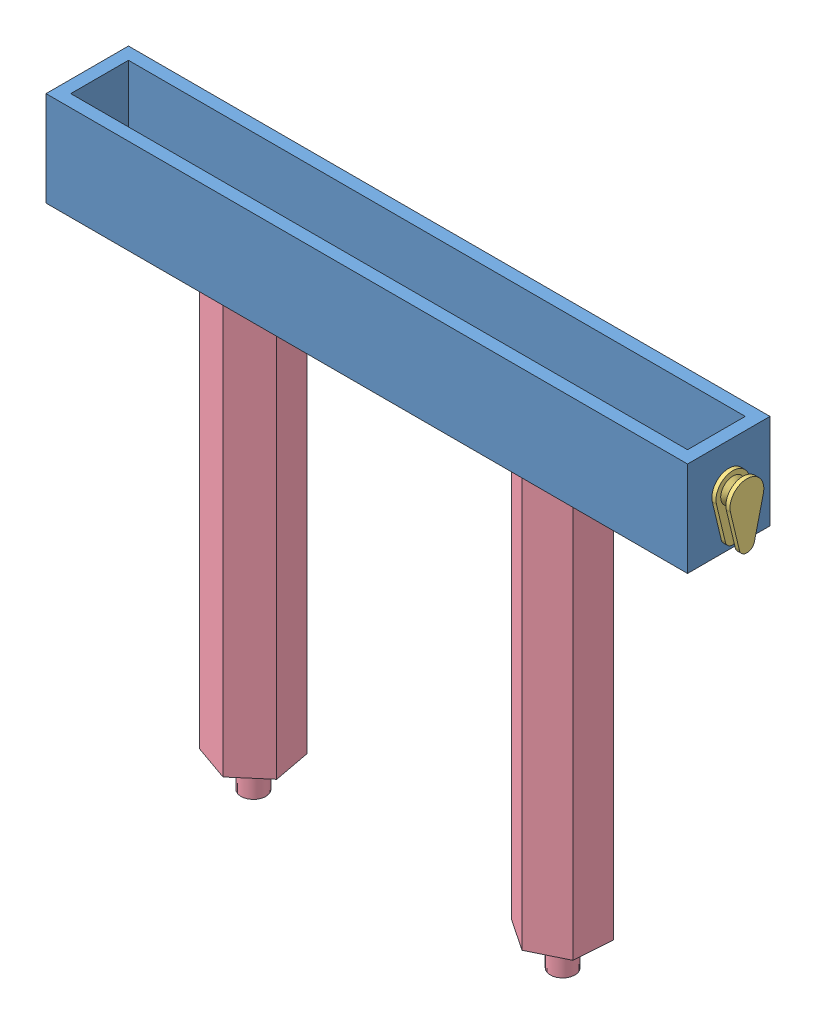
SolidWorks assembly 装配体3, configuration Default. Lengths in mm.
Overall size (164.4 131 49).
8 component instances, 4 part files, 4 mates.
Components (placement in the parent):
- 出绳点链接板（150）-1: 出绳点链接板（150） [默认] at (-22.0364 18.7488 21.8911) size (164.4 31 49)
  - 出绳点链接板（150）-1: 出绳点链接板（150） [默认] at (-17.762 -8.3386 0) size (155.6 23 20)
  - 柱塞螺丝M6-1: 柱塞螺丝M6 [默认] at (-55.262 -1.5986 0) x (0.837169 0 0.546944) z (0.546944 0 -0.837169) size (12 14.74 12)
  - 柱塞螺丝M6-2: 柱塞螺丝M6 [默认] at (19.738 -1.5986 0) x (-0.837169 0 -0.546944) z (-0.546944 0 0.837169) size (12 14.74 12)
  - 零件1^latest1-1: 零件1^latest1 [默认] at (-99.962 140.6589 -24.5142) x (0 0.000105 1) z (1 0 0) size (28.6 15.58 4.4)
  - 零件1^latest1-2: 零件1^latest1 [默认] at (64.438 140.6589 24.5142) x (0 0.000105 -1) z (-1 0 0) size (28.6 15.58 4.4)
- 单头六角柱100-1: 单头六角柱100 [默认] at (-77.2984 10.4102 21.8911) x (-0.757643 0 0.65267) z (0.65267 0 0.757643) size (18.48 108 16.01)
- 单头六角柱100-2: 单头六角柱100 [默认] at (-2.2984 10.4102 21.8911) x (-0.897655 0 0.4407) z (0.4407 0 0.897655) size (18.48 108 16.01)
Mates (geometry in assembly coordinates):
- 同心1: concentric aligned: cylinder of 出绳点链接板（150）-1/柱塞螺丝M6-1 through (-77.2984 2.4102 21.8911) axis (0 1 0) radius 3; cylinder of 单头六角柱100-1 through (-77.2984 -46.9586 21.8911) axis (0 1 0) radius 3
- 同心2: concentric aligned: cylinder of 出绳点链接板（150）-1/柱塞螺丝M6-2 through (-2.2984 2.4102 21.8911) axis (0 1 0) radius 3; cylinder of 单头六角柱100-2 through (-2.2984 -46.9586 21.8911) axis (0 1 0) radius 3
- 重合2: coincident aligned: plane of 单头六角柱100-1 through (-77.2984 10.4102 21.8911) normal (0 1 0); plane of 单头六角柱100-2 through (-2.2984 10.4102 21.8911) normal (0 1 0)
- 重合3: coincident anti-aligned: plane of 出绳点链接板（150）-1/出绳点链接板（150）-1 through (-39.7984 10.4102 21.8911) normal (0 -1 0); plane of 单头六角柱100-1 through (-77.2984 10.4102 21.8911) normal (0 1 0)
